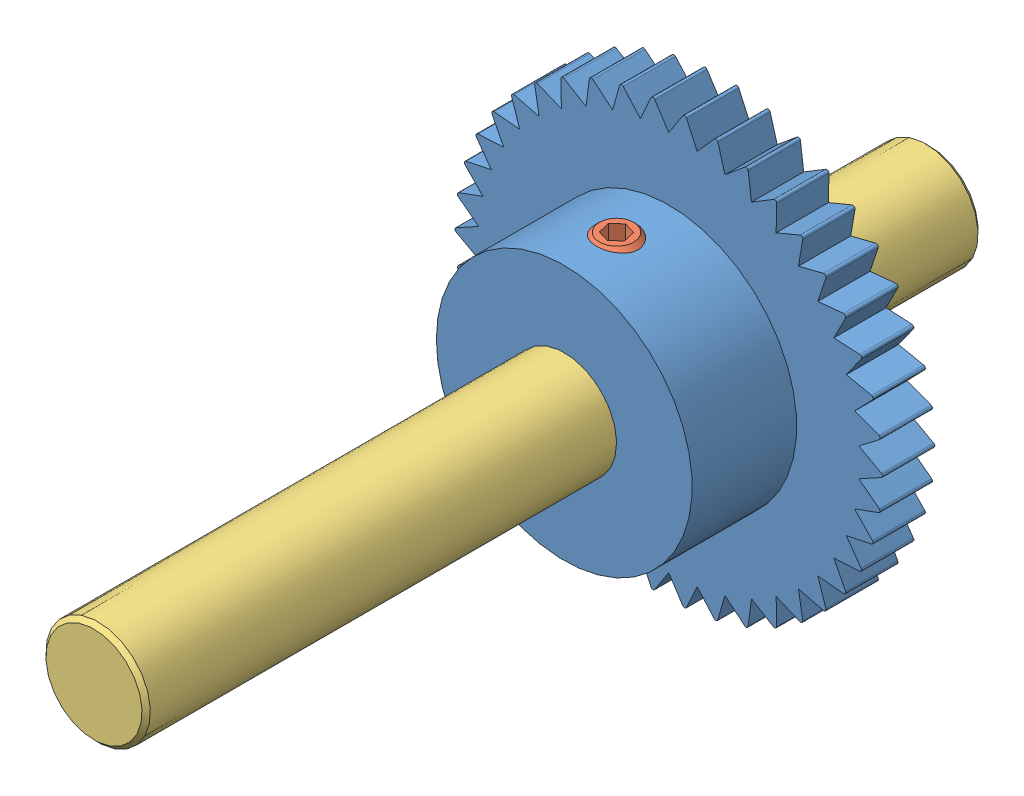
SolidWorks assembly Gear Assy., configuration Default. Lengths in mm.
Overall size (25.98 25.91 50.8).
3 component instances, 3 part files, 4 mates.
Components (placement in the parent):
- Gear-1: Gear [Default] at (-6.0116 12.97 -10.4019) size (25.98 25.91 9.53)
- Socket Set Screw Cup Point_AI-2: Socket Set Screw Cup Point_AI [SSCUPSKT 0.112-40x0.1875-HX-N] at (-6.0116 20.8948 -4.0519) x (0 -1 0) z (0.957084 0 0.28981) size (4.76 2.84 2.84)
- Sample Gear Shaft-1: Sample Gear Shaft [Default] at (-6.0116 12.97 27.6981) x (0 0 1) z (-0.319949 0.947435 0) size (50.8 6.35 6.35)
Mates (geometry in assembly coordinates):
- Concentric3: concentric: cylinder of Gear-1 through (-6.0116 0.0166 -4.0519) axis (0 1 0) radius 1.1303; cylinder of Socket Set Screw Cup Point_AI-2 through (-6.0116 44.8136 -4.0519) axis (0 1 0) radius 1.4224
- Concentric4: concentric anti-aligned: cylinder of Gear-1 through (-6.0116 12.97 -17.1874) axis (0 0 -1) radius 3.175; cylinder of Sample Gear Shaft-1 through (-6.0116 12.97 -23.1019) axis (0 0 1) radius 3.175
- Distance2: distance = 12.7 mm aligned: plane of Sample Gear Shaft-1 through (-6.0116 12.97 -23.1019) normal (0 0 -1); plane of Gear-1 through (-6.0116 16.145 -10.4019) normal (0 0 -1)
- Distance3: distance = 7.9248 mm aligned: plane of Gear-1 through (-6.0116 12.97 -10.4019) normal (0 1 0); plane of Socket Set Screw Cup Point_AI-2 through (-6.0116 20.8948 -4.0519) normal (0 1 0)
